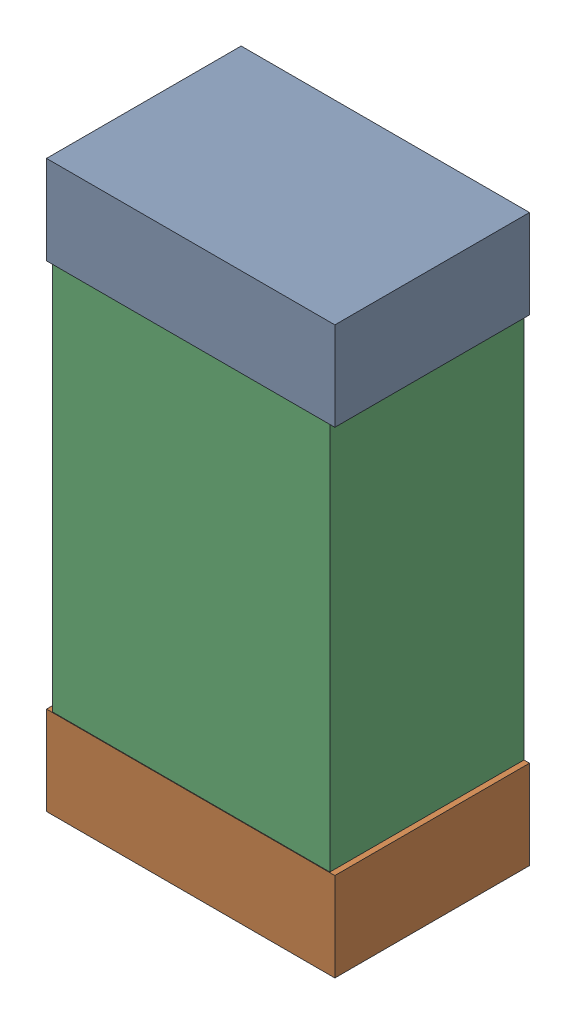
SolidWorks assembly C10, configuration Default. Lengths in mm.
Overall size (0.52 1.02 0.35).
6 component instances, 2 part files, 0 mates.
Components (placement in the parent):
- 870941120-1: 870941120 [Default] at (56.2348 25.4722 0) size (0.52 0.16 0.35)
  - Extruded_3-1: Extruded_3 [Default] at origin size (0.52 0.16 0.35)
- 870941120-2: 870941120 [Default] at (56.2348 24.6122 0) size (0.52 0.16 0.35)
  - Extruded_3-1: Extruded_3 [Default] at origin size (0.52 0.16 0.35)
- 870941280-1: 870941280 [Default] at (56.2348 25.0422 0) size (0.5 1 0.35)
  - Extruded_4-1: Extruded_4 [Default] at origin size (0.5 1 0.35)
